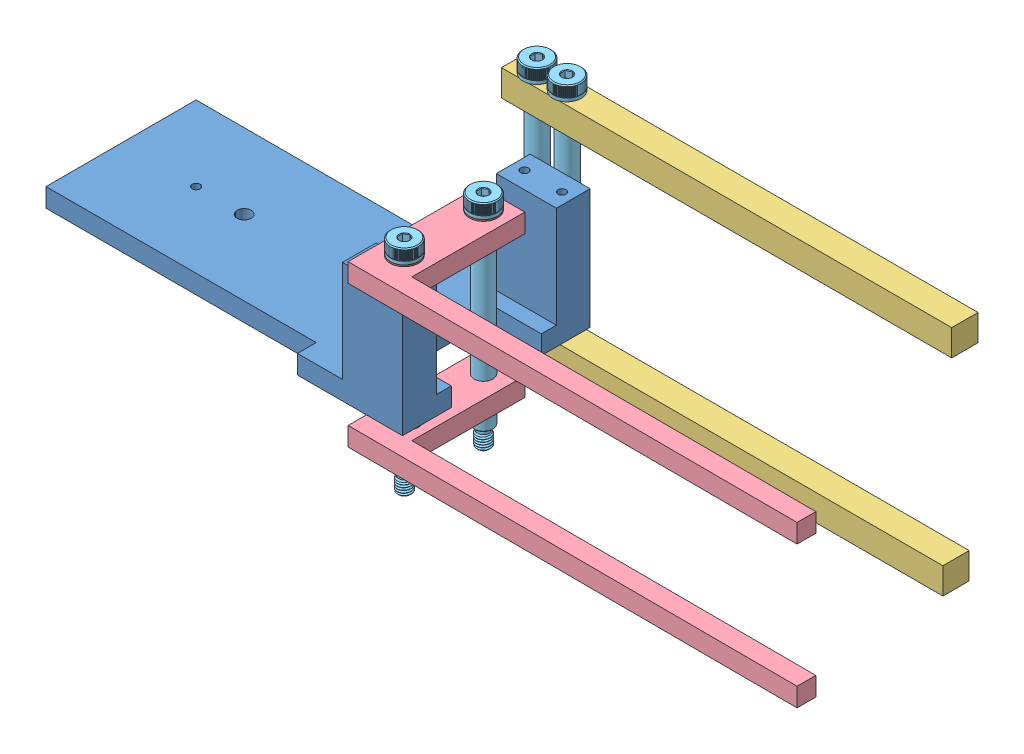
SolidWorks assembly Final ESP Claw Assembly, configuration Default. Lengths in mm.
Overall size (266.8 76.56 90.45).
15 component instances, 5 part files, 20 mates.
Components (placement in the parent):
- Baseplate-1: Baseplate [Default] at (-26.7248 52.3845 146.0384) size (127 40.64 63.5)
- 95606A110-1: 95606A110 [95606A110] at (95.1952 87.1825 133.9734) x (0 -1 0) z (0 0 1) size (0.51 9.53 9.53)
- 95606A110-2: 95606A110 [95606A110] at (95.1952 45.5265 133.9734) x (0 1 0) z (0 0 1) size (0.51 9.53 9.53)
- Claw of stationary part-1: Claw of stationary part [Default] at (134.8516 86.6745 60.1541) x (1 0 0) z (0 1 0) size (152.4 8.89 8.89)
- Claw of stationary part-2: Claw of stationary part [Default] at (153.6152 46.0345 81.9034) x (1 0 0) z (0 -1 0) size (152.4 8.89 8.89)
- Claw of moving part-1: Claw of moving part [Default] at (102.7993 87.1825 139.0581) x (0.999995 0 0.003146) z (0 1 0) size (152.4 44.45 6.35)
- Claw of moving part-2: Claw of moving part [Default] at (102.7993 39.1765 139.0581) x (0.999995 0 0.003146) z (0 1 0) size (152.4 44.45 6.35)
- 95606A110-3: 95606A110 [95606A110] at (95.1952 94.0405 133.9734) x (0 -1 0) z (0 0 1) size (0.51 9.53 9.53)
- 95606A110-4: 95606A110 [95606A110] at (95.1952 38.6685 133.9734) x (0 1 0) z (0 0 1) size (0.51 9.53 9.53)
- 97345A191-1: 97345A191 [97345A191] at (95.1952 98.803 133.9734) x (1 0 0) z (0 1 0) size (9.53 9.53 75.03)
- 97345A191-2: 97345A191 [97345A191] at (95.2792 98.803 107.2843) x (1 0 0) z (0 1 0) size (9.53 9.53 75.03)
- 95606A110-5: 95606A110 [95606A110] at (95.2792 94.0405 107.2843) x (0 -1 0) z (0 0 1) size (0.51 9.53 9.53)
- 95606A110-6: 95606A110 [95606A110] at (95.2792 38.6685 107.2843) x (0 1 0) z (0 0 1) size (0.51 9.53 9.53)
- 97345A191-3: 97345A191 [97345A191] at (66.2716 100.327 60.1541) x (1 0 0) z (0 1 0) size (9.53 9.53 75.03)
- 97345A191-4: 97345A191 [97345A191] at (76.4316 100.327 60.1541) x (1 0 0) z (0 1 0) size (9.53 9.53 75.03)
Mates (geometry in assembly coordinates):
- Coincident1: coincident anti-aligned: circle of Baseplate-1; circle of 95606A110-1
- Coincident3: coincident anti-aligned: plane of Baseplate-1 through (-26.7248 46.0345 146.0384) normal (0 -1 0); plane of 95606A110-2 through (95.1952 46.0345 133.9734) normal (0 1 0)
- Coincident5: coincident anti-aligned: plane of Baseplate-1 through (-26.7248 86.6745 146.0384) normal (0 1 0); plane of Claw of stationary part-1 through (134.8516 86.6745 60.1541) normal (0 -1 0)
- Coincident6: coincident anti-aligned: plane of Baseplate-1 through (-26.7248 46.0345 146.0384) normal (0 -1 0); plane of Claw of stationary part-2 through (153.6152 46.0345 81.9034) normal (0 1 0)
- Coincident7: coincident aligned: circle of 95606A110-1; circle of Claw of moving part-1
- Coincident9: coincident aligned: plane of Claw of moving part-1 through (239.9586 93.5325 139.4895) normal (0.003146 0 -0.999995); plane of Claw of moving part-2 through (239.9586 45.5265 139.4895) normal (0.003146 0 -0.999995)
- Coincident10: coincident aligned: circle of Claw of moving part-1; circle of 95606A110-3
- Coincident11: coincident anti-aligned: circle of Claw of moving part-2; circle of 95606A110-4
- Coincident13: coincident anti-aligned: circle of 95606A110-2; circle of Claw of moving part-2
- Coincident14: coincident anti-aligned: plane of 95606A110-3 through (95.1952 94.0405 133.9734) normal (0 1 0); plane of 97345A191-1 through (95.1952 94.0405 138.7359) normal (0 -1 0)
- Coincident15: coincident anti-aligned: plane of 95606A110-3 through (95.1952 94.0405 133.9734) normal (0 1 0); plane of 97345A191-1 through (95.1952 94.0405 138.7359) normal (0 -1 0)
- Concentric4: concentric aligned: cylinder of Claw of moving part-1 through (95.1952 87.1825 133.9734) axis (0 -1 0) radius 3.175; cylinder of 97345A191-1 through (95.1952 24.1905 133.9734) axis (0 -1 0) radius 3.175
- Coincident17: coincident aligned: circle of Claw of moving part-1; circle of 95606A110-5
- Coincident18: coincident anti-aligned: circle of Claw of moving part-2; circle of 95606A110-6
- Coincident19: coincident anti-aligned: plane of 97345A191-2 through (95.2792 94.0405 112.0468) normal (0 -1 0); plane of 95606A110-5 through (95.2792 94.0405 107.2843) normal (0 1 0)
- Concentric5: concentric aligned: cylinder of Claw of moving part-1 through (95.2792 87.1825 107.2843) axis (0 -1 0) radius 3.175; cylinder of 97345A191-2 through (95.2792 24.1905 107.2843) axis (0 -1 0) radius 3.175
- Coincident20: coincident anti-aligned: circle of Claw of stationary part-1; plane of 97345A191-3 through (66.2716 95.5645 64.9166) normal (0 -1 0)
- Concentric6: concentric anti-aligned: cylinder of Claw of stationary part-1 through (66.2716 95.5645 60.1541) axis (0 1 0) radius 3.175; cylinder of 97345A191-3 through (66.2716 25.7145 60.1541) axis (0 -1 0) radius 3.175
- Concentric7: concentric anti-aligned: cylinder of Claw of stationary part-1 through (76.4316 95.5645 60.1541) axis (0 1 0) radius 3.175; cylinder of 97345A191-4 through (76.4316 25.7145 60.1541) axis (0 -1 0) radius 3.175
- Coincident21: coincident anti-aligned: plane of Claw of stationary part-1 through (134.8516 95.5645 60.1541) normal (0 1 0); plane of 97345A191-4 through (76.4316 95.5645 64.9166) normal (0 -1 0)
